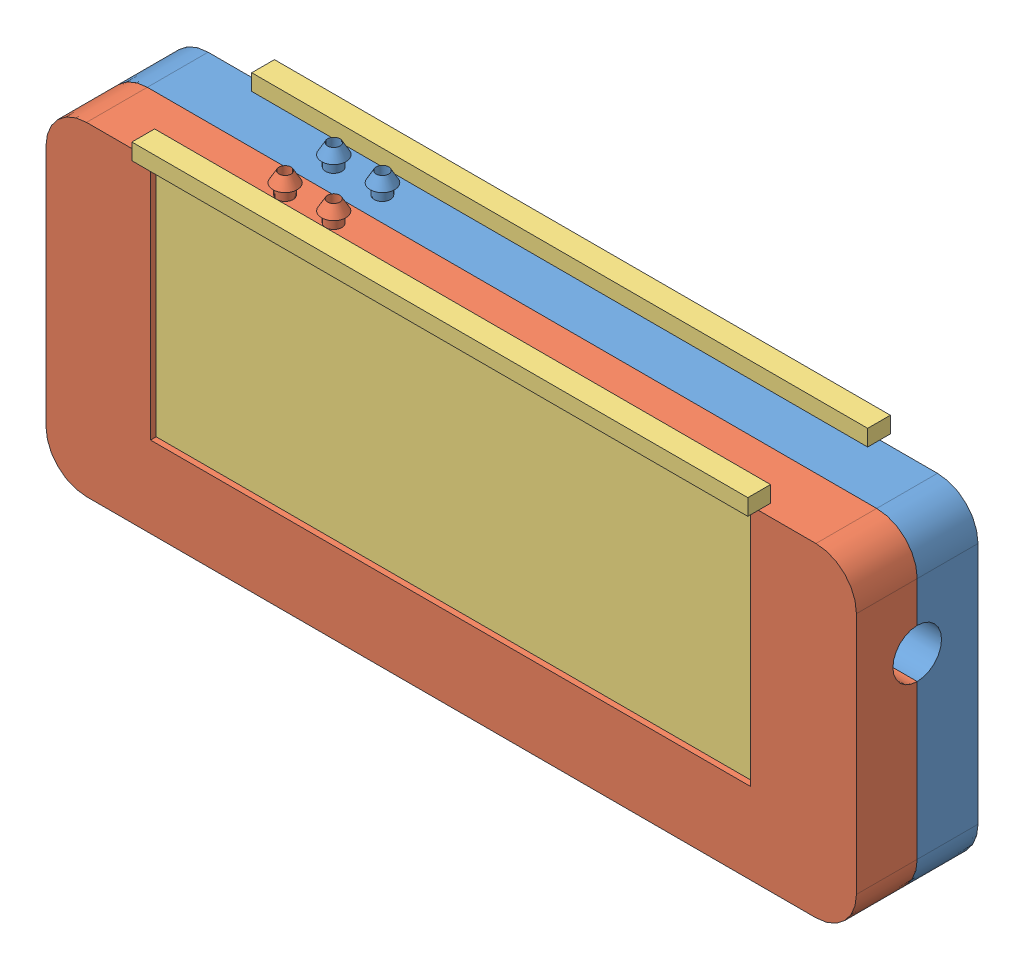
SolidWorks assembly Molde Batman, configuration Predeterminado. Lengths in mm.
Overall size (100 45.4 17.6).
4 component instances, 3 part files, 10 mates.
Components (placement in the parent):
- MoldeBatmanLado2-1: MoldeBatmanLado2 [Predeterminado] at (-27.753 -4.051 94.75) size (100 45.2 10.5)
- MoldeBatmanLado1-1: MoldeBatmanLado1 [Predeterminado] at (-27.753 -4.051 109.75) size (100 45.4 7.72)
- MoldeBatmanTapas-1: MoldeBatmanTapas [Predeterminado] at (-40.8672 -12.051 96.25) x (-1 0 0) z (0 0 -1) size (76 32 2.8)
- MoldeBatmanTapas-2: MoldeBatmanTapas [Predeterminado] at (35.147 -12.051 108.25) size (76 32 2.8)
Mates (geometry in assembly coordinates):
- Paralelo1: parallel anti-aligned: plane of MoldeBatmanLado2-1 through (-27.753 -14.051 94.75) normal (0 1 0); plane of MoldeBatmanTapas-1 through (35.1328 -14.051 95.45) normal (0 -1 0)
- Coincidente2: coincident anti-aligned: plane of MoldeBatmanLado2-1 through (-27.753 -14.051 96.25) normal (0 0 -1); plane of MoldeBatmanTapas-1 through (-40.8672 -12.051 96.25) normal (0 0 1)
- Coincidente3: coincident anti-aligned: plane of MoldeBatmanLado2-1 through (-40.8672 -14.051 94.75) normal (1 0 0); plane of MoldeBatmanTapas-1 through (-40.8672 17.949 95.45) normal (-1 0 0)
- Coincidente4: coincident anti-aligned: plane of MoldeBatmanLado1-1 through (-40.853 -14.051 108.25) normal (0 0 1); plane of MoldeBatmanTapas-2 through (35.147 -12.051 108.25) normal (0 0 -1)
- Coincidente5: coincident anti-aligned: plane of MoldeBatmanLado1-1 through (35.147 -14.051 109.05) normal (-1 0 0); plane of MoldeBatmanTapas-2 through (35.147 17.949 109.05) normal (1 0 0)
- Coincidente6: coincident aligned: plane of MoldeBatmanLado2-1 through (47.247 15.949 102.25) normal (1 0 0); plane of MoldeBatmanLado1-1 through (47.247 15.949 102.25) normal (1 0 0)
- Coincidente7: coincident aligned: plane of MoldeBatmanLado2-1 through (-52.753 15.949 102.25) normal (0 1 0); plane of MoldeBatmanLado1-1 through (-52.753 15.949 102.25) normal (0 1 0)
- Distancia límite1: limit distance = 0 mm anti-aligned: plane of MoldeBatmanTapas-1 through (35.1328 -14.051 95.45) normal (0 -1 0); plane of MoldeBatmanLado2-1 through (-27.753 -14.051 94.75) normal (0 1 0)
- Distancia límite2: limit distance = 0 mm anti-aligned: plane of MoldeBatmanTapas-2 through (-40.853 -14.051 109.05) normal (0 -1 0); plane of MoldeBatmanLado1-1 through (-27.753 -14.051 109.75) normal (0 1 0)
- Distancia límite5: limit distance = 0 mm anti-aligned: plane of MoldeBatmanLado2-1 through (-27.753 -4.051 102.25) normal (0 0 1); plane of MoldeBatmanLado1-1 through (-27.753 -4.051 102.25) normal (0 0 -1)
